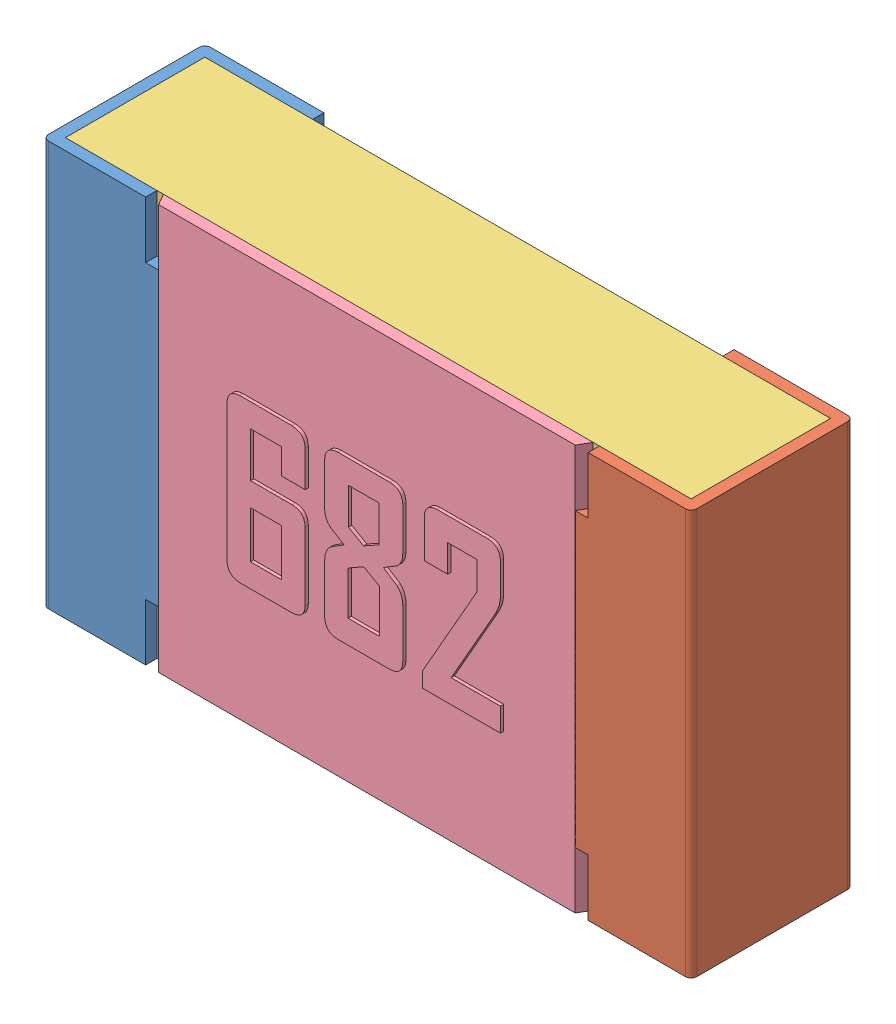
SolidWorks assembly Resistor_0805, configuration Default. Lengths in mm.
Overall size (2 1.25 0.51).
4 component instances, 4 part files, 0 mates.
Components (placement in the parent):
- Pin1Body-1: Pin1Body [Default] at (0 0 0.01) size (0.37 1.25 0.5)
- Pin2Body-1: Pin2Body [Default] at (0 0 0.01) size (0.37 1.25 0.5)
- CeramicBody-1: CeramicBody [Default] at (0 0 0.01) size (1.93 1.25 0.43)
- CoatingBody-1: CoatingBody [Default] at (0 0 0.01) size (1.33 1.25 0.05)
